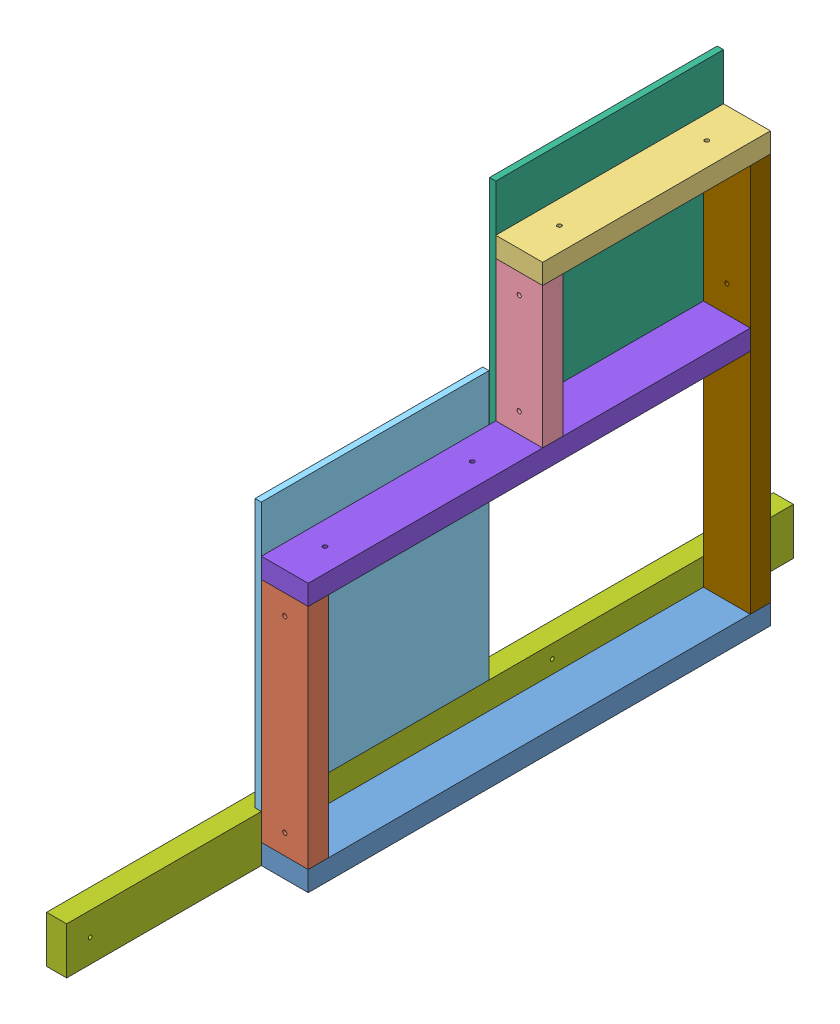
SolidWorks assembly TE-23039, configuration Default. Lengths in mm.
Overall size (127 901.7 1377.95).
9 component instances, 9 part files, 24 mates.
Components (placement in the parent):
- TE-23018-1: TE-23018 [Default] at (44.45 19.05 -0.0635) x (0 -1 0) z (0 0 1) size (38.1 88.9 876.3)
- TE-23019-1: TE-23019 [Default] at (44.45 469.9 857.1865) x (0 0 -1) z (0 -1 0) size (38.1 88.9 431.8)
- TE-23023-1: TE-23023 [Default] at (44.45 793.75 -0.0635) x (0 -1 0) z (0 0 1) size (38.1 88.9 431.8)
- TE-23022-1: TE-23022 [Default] at (44.45 508 412.6865) x (0 0 1) z (0 1 0) size (38.1 88.9 266.7)
- TE-23024-1: TE-23024 [Default] at (-11.9062 342.9 660.3365) x (0 0 -1) z (0 -1 0) size (431.8 11.91 508)
- TE-23025-1: TE-23025 [Default] at (-11.9062 685.8 215.8365) x (0 0 1) z (0 1 0) size (431.8 11.91 431.8)
- TE-23005-1: TE-23005 [Default] at (-19.05 44.45 -132.6198) size (38.1 88.9 1377.95)
- TE-23021-1: TE-23021 [Default] at (44.45 488.95 38.0365) x (0 1 0) z (0 0 1) size (38.1 88.9 838.2)
- TE-23020-1: TE-23020 [Default] at (44.45 38.1 18.9865) x (0 0 -1) z (0 1 0) size (38.1 88.9 736.6)
Mates (geometry in assembly coordinates):
- Coincident5: coincident anti-aligned: plane of Cube Shelf Long Horizontal-1 through (0 38.1 876.2365) normal (0 1 0); plane of TE-23019-1 through (44.45 38.1 857.1865) normal (0 -1 0)
- Coincident6: coincident aligned: plane of Cube Shelf Long Horizontal-1 through (44.45 19.05 876.2365) normal (0 0 1); plane of TE-23019-1 through (0 38.1 876.2365) normal (0 0 1)
- Coincident7: coincident aligned: plane of Cube Shelf Long Horizontal-1 through (0 38.1 876.2365) normal (-1 0 0); plane of TE-23019-1 through (0 38.1 876.2365) normal (-1 0 0)
- Distance4: distance = 88.9 mm aligned: plane of Cube Shelf Long Horizontal-1 through (0 0 876.2365) normal (0 -1 0); plane of TE-23024-1 through (0 88.9 876.2365) normal (0 -1 0)
- Coincident112: coincident anti-aligned: plane of Cube Shelf Long Horizontal-1 through (0 38.1 876.2365) normal (-1 0 0); plane of Cone Ramp Horizontal no holes-1 through (0 0 1245.3302) normal (1 0 0)
- Coincident114: coincident aligned: plane of Cube Shelf Long Horizontal-1 through (0 0 876.2365) normal (0 -1 0); plane of Cone Ramp Horizontal no holes-1 through (-38.1 0 1245.3302) normal (0 -1 0)
- Coincident130: coincident anti-aligned: plane of Cube Shelf Long Horizontal-1 through (0 38.1 876.2365) normal (0 1 0); plane of TE-23020-1 through (44.45 38.1 18.9865) normal (0 -1 0)
- Coincident131: coincident aligned: plane of Cube Shelf Long Horizontal-1 through (44.45 19.05 -0.0635) normal (0 0 -1); plane of TE-23020-1 through (88.9 774.7 -0.0635) normal (0 0 -1)
- Coincident132: coincident aligned: plane of Cube Shelf Long Horizontal-1 through (88.9 38.1 876.2365) normal (1 0 0); plane of TE-23020-1 through (88.9 774.7 38.0365) normal (1 0 0)
- Coincident154: coincident anti-aligned: plane of TE-23019-1 through (0 38.1 876.2365) normal (-1 0 0); plane of TE-23024-1 through (0 342.9 660.3365) normal (1 0 0)
- Coincident48: coincident anti-aligned: plane of Cube Shelf Short Horizontal-1 through (0 774.7 431.7365) normal (0 -1 0); plane of TE-23022-1 through (44.45 774.7 412.6865) normal (0 1 0)
- Coincident49: coincident aligned: plane of Cube Shelf Short Horizontal-1 through (88.9 812.8 431.7365) normal (1 0 0); plane of TE-23022-1 through (88.9 774.7 393.6365) normal (1 0 0)
- Coincident50: coincident aligned: plane of Cube Shelf Short Horizontal-1 through (44.45 793.75 431.7365) normal (0 0 1); plane of TE-23022-1 through (0 774.7 431.7365) normal (0 0 1)
- Coincident90: coincident anti-aligned: plane of Cube Shelf Short Horizontal-1 through (0 812.8 431.7365) normal (-1 0 0); plane of TE-23025-1 through (0 685.8 215.8365) normal (1 0 0)
- Coincident137: coincident aligned: plane of Cube Shelf Short Horizontal-1 through (88.9 812.8 431.7365) normal (1 0 0); plane of TE-23020-1 through (88.9 774.7 38.0365) normal (1 0 0)
- Coincident138: coincident aligned: plane of Cube Shelf Short Horizontal-1 through (44.45 793.75 -0.0635) normal (0 0 -1); plane of TE-23020-1 through (88.9 774.7 -0.0635) normal (0 0 -1)
- Coincident148: coincident anti-aligned: plane of Cube Shelf Short Horizontal-1 through (0 774.7 431.7365) normal (0 -1 0); plane of TE-23020-1 through (44.45 774.7 18.9865) normal (0 1 0)
- Coincident139: coincident anti-aligned: plane of TE-23022-1 through (44.45 508 412.6865) normal (0 -1 0); plane of TE-23021-1 through (88.9 508 876.2365) normal (0 1 0)
- Coincident140: coincident aligned: plane of TE-23022-1 through (88.9 774.7 393.6365) normal (1 0 0); plane of TE-23021-1 through (88.9 469.9 876.2365) normal (1 0 0)
- Coincident141: coincident anti-aligned: plane of TE-23021-1 through (44.45 488.95 38.0365) normal (0 0 -1); plane of TE-23020-1 through (88.9 774.7 38.0365) normal (0 0 1)
- Distance6: distance = 369.0938 mm aligned: plane of Cone Ramp Horizontal no holes-1 through (-19.05 44.45 1245.3302) normal (0 0 1); plane of TE-23019-1 through (0 38.1 876.2365) normal (0 0 1)
- Coincident157: coincident aligned: plane of TE-23022-1 through (0 774.7 431.7365) normal (0 0 1); plane of TE-23025-1 through (0 901.7 431.7365) normal (0 0 1)
- Distance7: distance = 88.9 mm aligned: plane of TE-23025-1 through (0 901.7 -0.0635) normal (0 1 0); plane of Cube Shelf Short Horizontal-1 through (0 812.8 431.7365) normal (0 1 0)
- Coincident159: coincident aligned: plane of TE-23024-1 through (0 88.9 876.2365) normal (0 0 1); plane of TE-23021-1 through (44.45 488.95 876.2365) normal (0 0 1)
